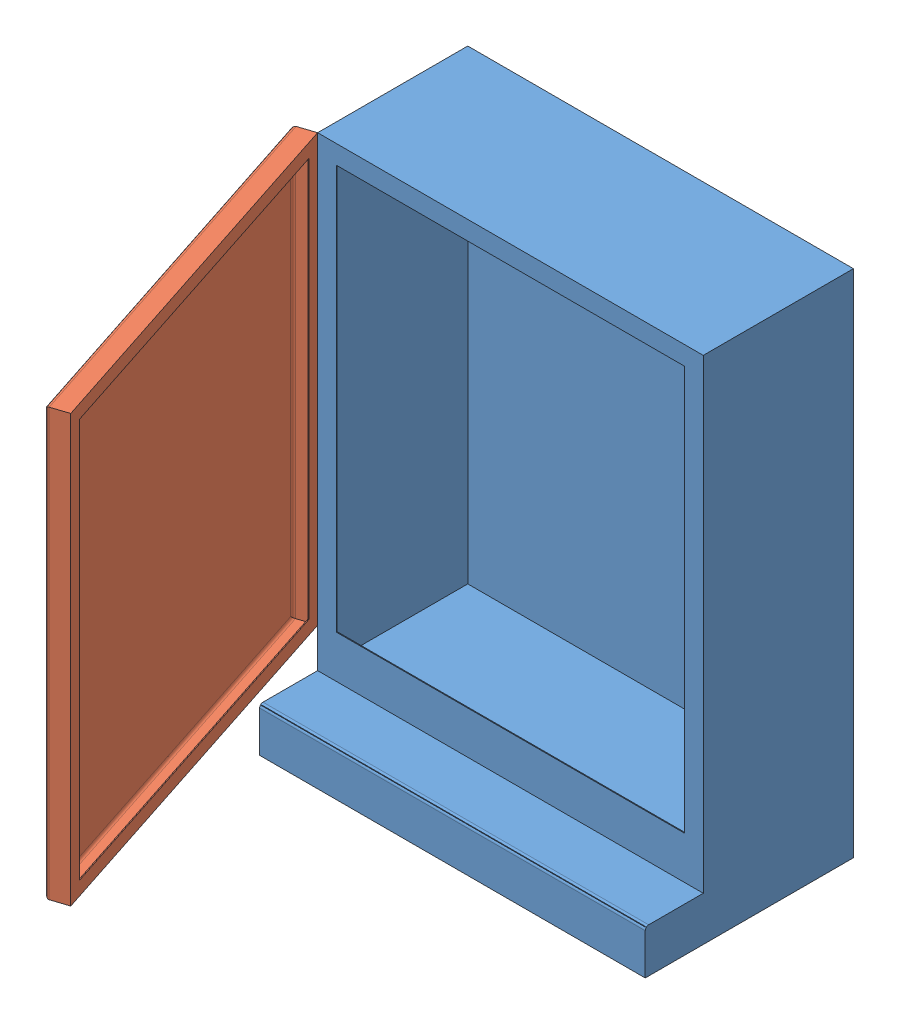
SolidWorks assembly toolchest me135 assembly, configuration Default. Lengths in mm.
Overall size (753.77 949.32 973.32).
2 component instances, 2 part files, 2 mates.
Components (placement in the parent):
- me135 toolchest-1: me135 toolchest [Default] at (137.8942 136.1635 1086.9795) size (717.55 949.32 387.35)
- door for me135 toolchest-1: door for me135 toolchest [Default] at (137.8942 291.7385 979.0295) x (0.31045 0 0.95059) z (-0.95059 0 0.31045) size (717.55 793.75 38.1)
Mates (geometry in assembly coordinates):
- Coincident3: coincident aligned: line of me135 toolchest-1 through (137.8942 1085.4885 979.0295) axis (0 -1 0); line of door for me135 toolchest-1 through (137.8942 1085.4885 979.0295) axis (0 -1 0)
- Coincident5: coincident aligned: plane of me135 toolchest-1 through (855.4442 1085.4885 699.6295) normal (0 1 0); plane of door for me135 toolchest-1 through (101.6767 1085.4885 990.8577) normal (0 1 0)
